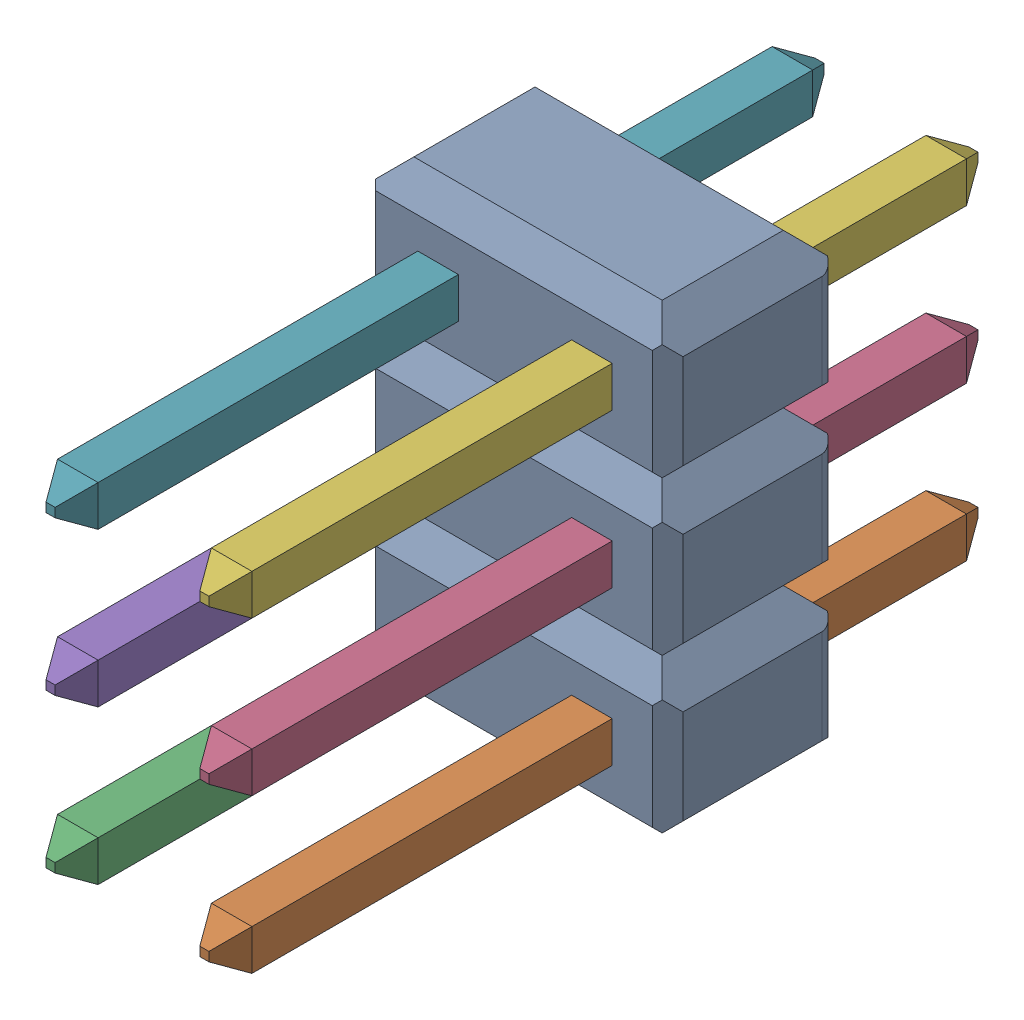
SolidWorks assembly 254-3X2, configuration ﾃﾞﾌｫﾙﾄ. Lengths in mm.
Overall size (5.08 7.62 12.7).
8 component instances, 2 part files, 0 mates.
Components (placement in the parent):
- User Library-2x3 TH Pitch 2_54mm-1: User Library-2x3 TH Pitch 2_54mm [ﾃﾞﾌｫﾙﾄ] at (0 -3.81 0) x (0 1 0) z (1 0 0) size (7.62 12.7 5.08)
  - header2x3-1: header2x3 [ﾃﾞﾌｫﾙﾄ] at (0 1.4 0) size (7.62 2.8 5.08)
  - pin-1: pin [ﾃﾞﾌｫﾙﾄ] at (1.29 -3.5 1.29) size (0.67 12.7 0.67)
  - pin-2: pin [ﾃﾞﾌｫﾙﾄ] at (1.29 -3.5 -1.25) size (0.67 12.7 0.67)
  - pin-3: pin [ﾃﾞﾌｫﾙﾄ] at (3.83 -3.5 1.29) size (0.67 12.7 0.67)
  - pin-4: pin [ﾃﾞﾌｫﾙﾄ] at (3.83 -3.5 -1.25) size (0.67 12.7 0.67)
  - pin-5: pin [ﾃﾞﾌｫﾙﾄ] at (6.37 -3.5 1.29) size (0.67 12.7 0.67)
  - pin-6: pin [ﾃﾞﾌｫﾙﾄ] at (6.37 -3.5 -1.25) size (0.67 12.7 0.67)
